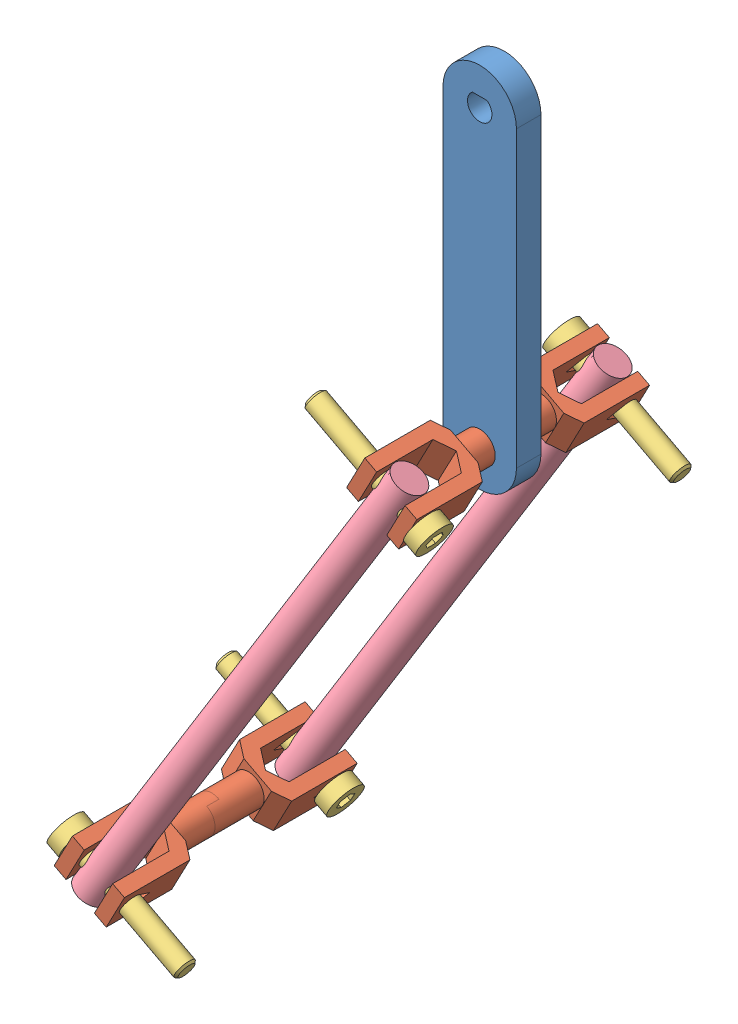
SolidWorks assembly Brazo, configuration Predeterminado. Lengths in mm.
Overall size (79.01 158.48 69.71).
13 component instances, 4 part files, 9 mates.
Components (placement in the parent):
- Eslabon-1: Eslabon [Predeterminado] at origin size (15 75 5)
- EjeDeRotacion-1: EjeDeRotacion [Predeterminado] at (0 -60 -2.5) x (-0.885247 0.465122 0) z (0 0 1) size (38 9.53 50.97)
  - MedioEjeRotacion-1: MedioEjeRotacion [Predeterminado] at origin size (12 8 25)
  - MedioEjeRotacion-2: MedioEjeRotacion [Predeterminado] at (0 0 2.5) x (-1 0 0) z (0 0 -1) size (12 8 25)
  - 07161-104x25-1: 07161-104x25 [Default] at (-6 0 22) x (1 0 0) z (0 -0.487842 0.872932) size (27.8 7 7)
  - 07161-104x25-2: 07161-104x25 [Default] at (6 0 -19.5) x (-1 0 0) z (0 0.890443 0.455095) size (27.8 7 7)
- eje-1: eje [Predeterminado] at (-20.4717 -98.9628 28.8706) x (0.885247 -0.465122 0) z (0.096855 0.18434 0.978079) size (6.35 98 6.35)
- eje-2: eje [Predeterminado] at (-20.4717 -98.9628 -12.6294) x (0.885247 -0.465122 0) z (0.096855 0.18434 0.978079) size (6.35 98 6.35)
- EjeDeRotacion-2: EjeDeRotacion [Predeterminado] at (-40.9433 -137.9257 16.2412) x (0.885247 -0.465122 0) z (0 0 1) size (38 9.53 50.97)
  - MedioEjeRotacion-1: MedioEjeRotacion [Predeterminado] at origin size (12 8 25)
  - MedioEjeRotacion-2: MedioEjeRotacion [Predeterminado] at (0 0 2.5) x (-1 0 0) z (0 0 -1) size (12 8 25)
  - 07161-104x25-1: 07161-104x25 [Default] at (-6 0 22) x (1 0 0) z (0 -0.487842 0.872932) size (27.8 7 7)
  - 07161-104x25-2: 07161-104x25 [Default] at (6 0 -19.5) x (-1 0 0) z (0 0.890443 0.455095) size (27.8 7 7)
Mates (geometry in assembly coordinates):
- Concéntrica1: concentric aligned: cylinder of Eslabon-1 through (0 -60 -2.5) axis (0 0 1) radius 3.175; cylinder of EjeDeRotacion-1/MedioEjeRotacion-2 through (0 -60 -10) axis (0 0 1) radius 3.175
- Coincidente1: coincident anti-aligned: plane of Eslabon-1 through (0 0 -2.5) normal (0 0 -1); circle of EjeDeRotacion-1/MedioEjeRotacion-1
- Concéntrica2: concentric aligned: cylinder of EjeDeRotacion-1/07161-104x25-1 through (-16.8197 -51.1627 19.5) axis (0.885247 -0.465122 0) radius 2; cylinder of eje-1 through (-2.8107 -58.5232 19.5) axis (0.885247 -0.465122 0) radius 2
- Coincidente2: coincident anti-aligned: plane of EjeDeRotacion-1 through (0 -60 -2.5) normal (-0.885247 0.465122 0); plane of eje-1 through (-20.4717 -98.9628 28.8706) normal (0.885247 -0.465122 0)
- Concéntrica3: concentric anti-aligned: cylinder of EjeDeRotacion-1/07161-104x25-2 through (16.8197 -68.8373 -22) axis (-0.885247 0.465122 0) radius 2; cylinder of eje-2 through (-2.8107 -58.5232 -22) axis (0.885247 -0.465122 0) radius 2
- Coincidente3: coincident anti-aligned: plane of EjeDeRotacion-1 through (0 -60 -2.5) normal (-0.885247 0.465122 0); plane of eje-2 through (-20.4717 -98.9628 -12.6294) normal (0.885247 -0.465122 0)
- Concéntrica4: concentric aligned: cylinder of eje-2 through (-43.754 -136.4489 -3.2588) axis (0.885247 -0.465122 0) radius 2; cylinder of EjeDeRotacion-2/07161-104x25-2 through (-57.763 -129.0884 -3.2588) axis (0.885247 -0.465122 0) radius 2
- Concéntrica5: concentric anti-aligned: cylinder of eje-1 through (-43.754 -136.4489 38.2412) axis (0.885247 -0.465122 0) radius 2; cylinder of EjeDeRotacion-2/07161-104x25-1 through (-24.1237 -146.763 38.2412) axis (-0.885247 0.465122 0) radius 2
- Coincidente4: coincident anti-aligned: plane of EjeDeRotacion-1 through (0 -60 -2.5) normal (-0.885247 0.465122 0); plane of EjeDeRotacion-2 through (-40.9433 -137.9257 16.2412) normal (0.885247 -0.465122 0)
